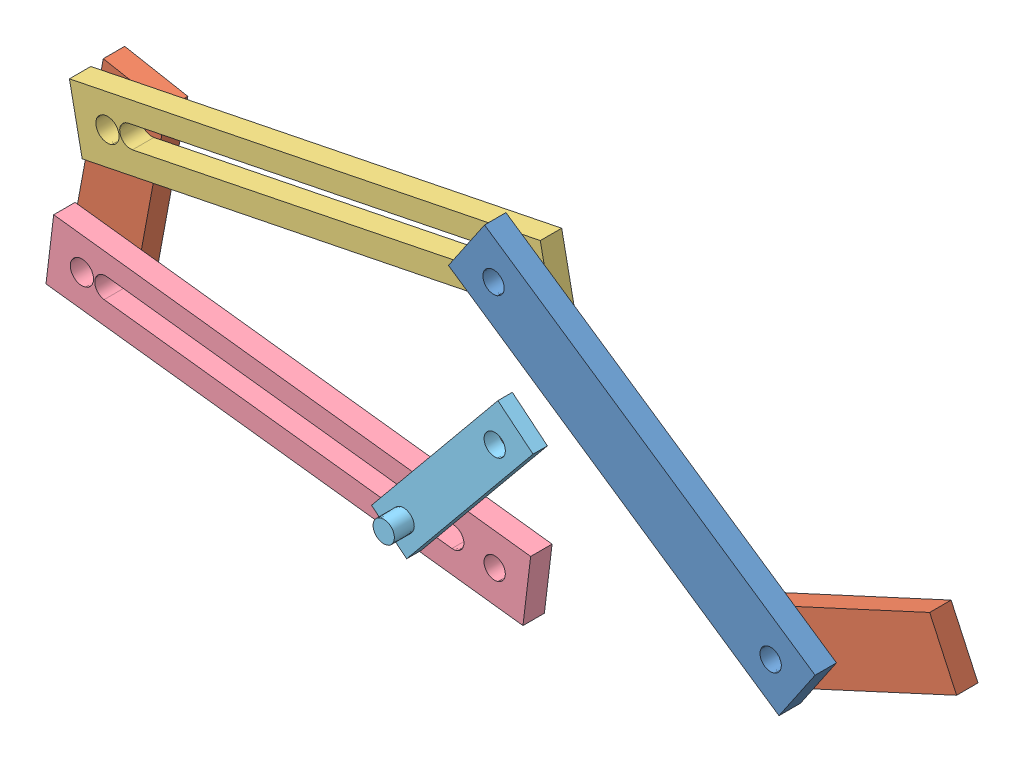
SolidWorks assembly Aeembly1111, configuration Default. Lengths in mm.
Overall size (118.76 83.88 9.14).
6 component instances, 5 part files, 8 mates.
Components (placement in the parent):
- C link-1: C link [Default] at (-3.615 -43.8463 46.8827) x (0.348931 -0.937148 0) z (0 0 1) size (43.08 33.67 2.54)
- F link-1: F link [Default] at (74.5703 -23.9814 44.3427) x (0.982934 -0.183958 0) z (0 0 1) size (23.67 19.89 2.54)
- T link-1: T link [Default] at (-3.2054 -22.8261 44.3427) x (0.914066 -0.405566 0) z (0 0 1) size (50.89 39.21 2.54)
- F link-2: F link [Default] at (-116.753 -30.4793 41.8027) x (-0.718058 -0.695983 0) z (0 0 1) size (23.67 19.89 2.54)
- base slider-1: base slider [Default] at (-18.9884 -57.3907 44.3427) x (0.740317 -0.672258 0) z (0 0 1) size (50.89 39.21 2.54)
- silderr-1: silderr [Default] at (-47.9169 -14.5662 46.8827) x (-0.964928 -0.262516 0) z (0 0 1) size (22.38 18.07 7.11)
Mates (geometry in assembly coordinates):
- Coincident1: coincident aligned: circle of C link-1; circle of T link-1
- Lock3: lock: unknown of C link-1; unknown of F link-1
- Concentric5: concentric aligned: circle of T link-1; circle of F link-2
- Coincident10: coincident anti-aligned: plane of T link-1 through (-3.2054 -22.8261 44.3427) normal (0 0 -1); plane of F link-2 through (-116.753 -30.4793 44.3427) normal (0 0 1)
- Concentric8: concentric: circle of F link-2; circle of base slider-1
- Coincident35: coincident anti-aligned: plane of F link-2 through (-116.753 -30.4793 44.3427) normal (0 0 1); plane of base slider-1 through (-18.9884 -57.3907 44.3427) normal (0 0 -1)
- Coincident40: coincident anti-aligned: plane of base slider-1 through (-18.9884 -57.3907 46.8827) normal (0 0 1); plane of silderr-1 through (-47.9169 -14.5662 46.8827) normal (0 0 -1)
- Slot5: slot anti-aligned: cylinder of silderr-1 through (-29.7947 -13.3135 43.8347) axis (0 0 1) radius 1.27; plane of base slider-1 through (-66.7298 -7.6097 54.5027) normal (-0.118945 -0.992901 0); cylinder of base slider-1 through (-25.616 -13.8141 54.5027) axis (0 0 -1) radius 1.27
